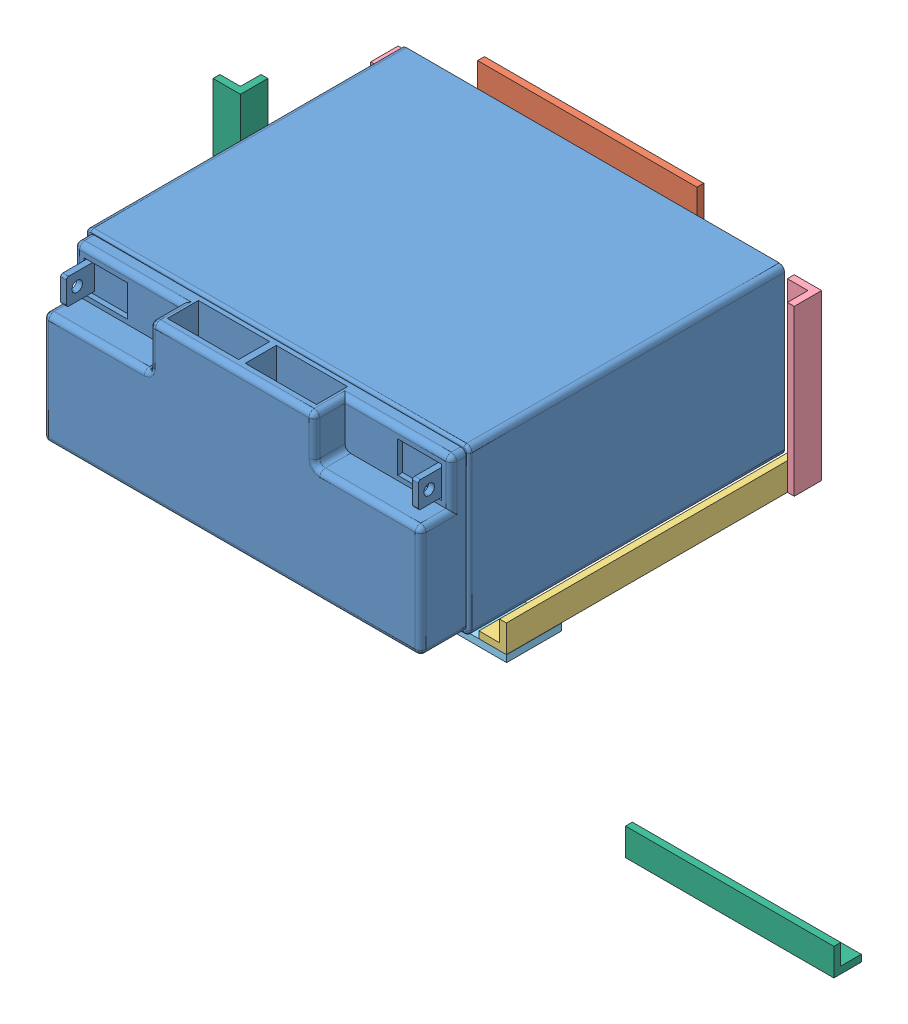
SolidWorks assembly Battery Box , configuration Default. Lengths in mm.
Overall size (221.5 283.19 176.08).
9 component instances, 6 part files, 22 mates.
Components (placement in the parent):
- Battery_12V-1: Battery_12V [Default] at (-13.3519 124.9193 60.0909) size (177.8 76.2 167.13)
- Bottom battery plate-1: Bottom battery plate [Default] at (35.3109 83.8261 56.9159) size (101.6 95.12 50.8)
- Battery angle bar 5.5in-1: Battery angle bar 5.5in [Default] at (-47.7349 39.0819 124.8294) x (0 0 1) z (-1 0 0) size (139.7 12.7 12.7)
- Battery angle bar 5.5in-2: Battery angle bar 5.5in [Default] at (135.7801 39.0819 128.7023) x (0 0 -1) z (1 0 0) size (139.7 12.7 12.7)
- Battery angle bar 3in-1: Battery angle bar 3in [Default] at (138.9551 59.4997 37.7366) x (0 1 0) z (1 0 0) size (76.2 12.7 12.7)
- Battery angle bar 3in-2: Battery angle bar 3in [Default] at (-70.0892 59.4997 56.9159) x (0 1 0) z (0 0 -1) size (76.2 12.7 12.7)
- Battery Connector Bar-1: Battery Connector Bar [Default] at (137.9889 51.9111 185.0208) x (0 1 0) z (1 0 0) size (3.17 25.4 189.99)
- Battery angle bar 3in left support-1: Battery angle bar 3in left support [Default] at (-54.0849 126.8726 145.9451) x (0 -1 0) z (1 0 0) size (96.52 12.7 12.7)
- Battery angle bar 3in left support-2: Battery angle bar 3in left support [Default] at (86.1079 -147.5834 60.6662) size (96.52 12.7 12.7)
Mates (geometry in assembly coordinates):
- Coincident1: coincident anti-aligned: plane of Battery_12V-1 through (-46.4649 138.9061 60.0909) normal (0 0 -1); plane of Bottom battery plate-1 through (35.3109 83.8261 60.0909) normal (0 0 1)
- Distance1: distance = 4.445 mm anti-aligned: plane of Battery_12V-1 through (-46.4649 62.7061 60.0909) normal (0 -1 0); plane of Bottom battery plate-1 through (35.3109 58.2611 56.9159) normal (0 1 0)
- Distance2: distance = 35.56 mm aligned: plane of Battery_12V-1 through (-46.4649 138.9061 206.1409) normal (-1 0 0); plane of Bottom battery plate-1 through (-10.9049 150.2091 60.0909) normal (-1 0 0)
- Distance3: distance = 4.445 mm aligned: plane of Battery angle bar 5.5in-1 through (-50.9099 39.0819 124.8294) normal (-1 0 0); plane of Battery_12V-1 through (-46.4649 138.9061 206.1409) normal (-1 0 0)
- Distance6: distance = 4.445 mm anti-aligned: plane of Battery angle bar 5.5in-1 through (-47.7349 58.2611 124.8294) normal (0 1 0); plane of Battery_12V-1 through (-46.4649 62.7061 60.0909) normal (0 -1 0)
- Coincident21: coincident aligned: plane of Bottom battery plate-1 through (35.3109 83.8261 56.9159) normal (0 0 -1); plane of Battery angle bar 5.5in-1 through (-50.9099 67.7861 56.9159) normal (0 0 -1)
- Distance7: distance = 4.445 mm anti-aligned: plane of Battery angle bar 5.5in-2 through (135.7801 39.0819 128.7023) normal (-1 0 0); plane of Battery_12V-1 through (131.3351 138.9061 60.0909) normal (1 0 0)
- Distance8: distance = 4.445 mm anti-aligned: plane of Battery angle bar 5.5in-2 through (135.7801 58.2611 128.7023) normal (0 1 0); plane of Battery_12V-1 through (-46.4649 62.7061 60.0909) normal (0 -1 0)
- Coincident31: coincident aligned: plane of Bottom battery plate-1 through (35.3109 83.8261 56.9159) normal (0 0 -1); plane of Battery angle bar 5.5in-2 through (138.9551 67.7861 56.9159) normal (0 0 -1)
- Coincident33: coincident anti-aligned: plane of Battery angle bar 5.5in-2 through (138.9551 39.0819 128.7023) normal (1 0 0); plane of Battery angle bar 3in-1 through (138.9551 59.4997 37.7366) normal (-1 0 0)
- Coincident34: coincident anti-aligned: plane of Battery angle bar 5.5in-2 through (138.9551 67.7861 56.9159) normal (0 0 -1); plane of Battery angle bar 3in-1 through (138.9551 59.4997 56.9159) normal (0 0 1)
- Coincident35: coincident aligned: plane of Battery angle bar 5.5in-2 through (138.9551 55.0861 196.6159) normal (0 -1 0); plane of Battery angle bar 3in-1 through (142.1301 55.0861 66.4409) normal (0 -1 0)
- Coincident41: coincident aligned: plane of Battery angle bar 5.5in-1 through (-50.9099 55.0861 56.9159) normal (0 -1 0); plane of Battery angle bar 3in-2 through (-41.3849 55.0861 53.7409) normal (0 -1 0)
- Parallel15: parallel anti-aligned: plane of Battery angle bar 5.5in-1 through (-50.9099 39.0819 124.8294) normal (-1 0 0); plane of Battery angle bar 3in-2 through (-50.9099 59.4997 56.9159) normal (1 0 0)
- Coincident46: coincident anti-aligned: plane of Battery angle bar 5.5in-1 through (-50.9099 67.7861 56.9159) normal (0 0 -1); plane of Battery angle bar 3in-2 through (-70.0892 59.4997 56.9159) normal (0 0 1)
- Coincident47: coincident anti-aligned: plane of Battery angle bar 5.5in-1 through (-50.9099 39.0819 124.8294) normal (-1 0 0); plane of Battery angle bar 3in-2 through (-50.9099 59.4997 56.9159) normal (1 0 0)
- Coincident53: coincident aligned: plane of Battery angle bar 5.5in-1 through (-50.9099 39.0819 124.8294) normal (-1 0 0); plane of Battery Connector Bar-1 through (-50.9099 55.0861 196.6159) normal (-1 0 0)
- Parallel20: parallel anti-aligned: plane of Battery angle bar 5.5in-1 through (-50.9099 55.0861 56.9159) normal (0 -1 0); plane of Battery Connector Bar-1 through (137.9889 55.0861 185.0208) normal (0 1 0)
- Coincident55: coincident anti-aligned: line of Battery angle bar 5.5in-2 through (138.9551 55.0861 196.6159) axis (-1 0 0); line of Battery Connector Bar-1 through (-50.9099 55.0861 196.6159) axis (1 0 0)
- Coincident61: coincident anti-aligned: plane of Battery angle bar 5.5in-1 through (-50.9099 39.0819 124.8294) normal (-1 0 0); plane of Battery angle bar 3in left support-1 through (-50.9099 126.8726 145.9451) normal (1 0 0)
- Coincident65: coincident anti-aligned: line of Battery angle bar 5.5in-1 through (-50.9099 55.0861 56.9159) axis (0 0 1); line of Battery angle bar 3in left support-1 through (-50.9099 55.0861 129.9409) axis (0 0 -1)
- Distance10: distance = 76.2 mm: line of Battery angle bar 3in left support-1 through (-50.9099 55.0861 129.9409) axis (-1 0 0); moEndPointRef_w of Battery angle bar 3in-2
